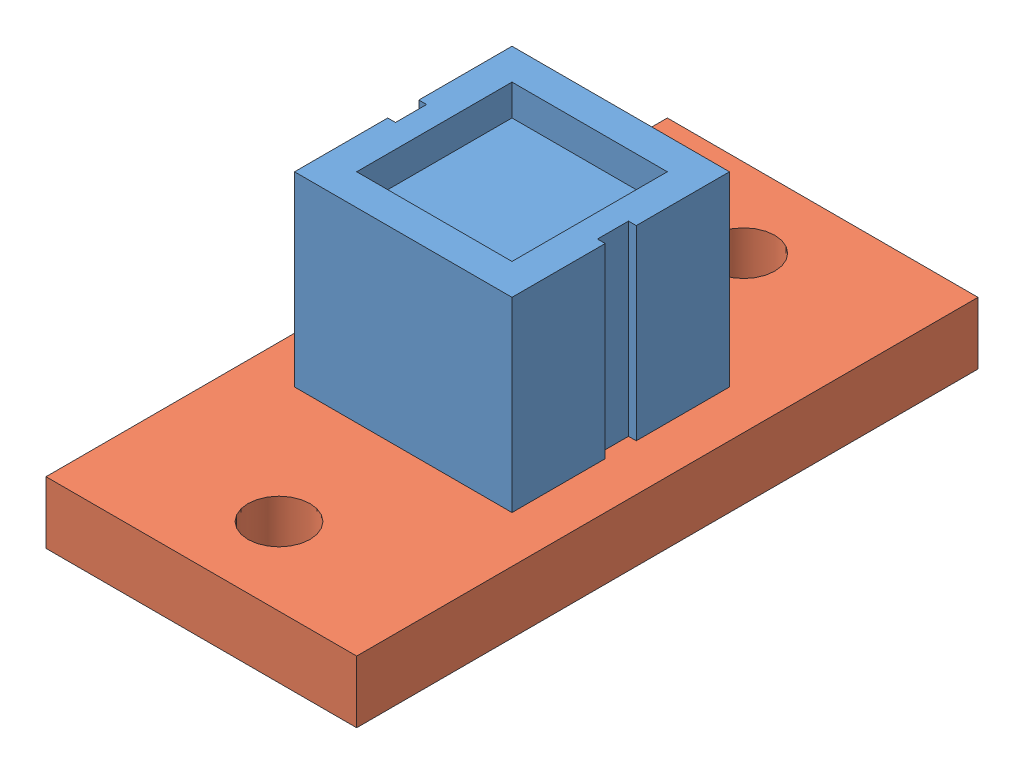
SolidWorks assembly placa cny70, configuration Predeterminado. Lengths in mm.
Overall size (10 9 20).
2 component instances, 2 part files, 2 mates.
Components (placement in the parent):
- cny70-1: cny70 [Predeterminado] at (-0.1516 0.386 9) size (7 9 7)
- cny70pcb-1: cny70pcb [Predeterminado] at (-0.1516 -1.614 9) size (10 2 20)
Mates (geometry in assembly coordinates):
- Coincidente1: coincident anti-aligned: plane of cny70-1 through (-0.1516 0.386 9) normal (0 -1 0); plane of cny70pcb-1 through (-0.1516 0.386 9) normal (0 1 0)
- Concéntrica1: concentric anti-aligned: circle of cny70-1; circle of cny70pcb-1
